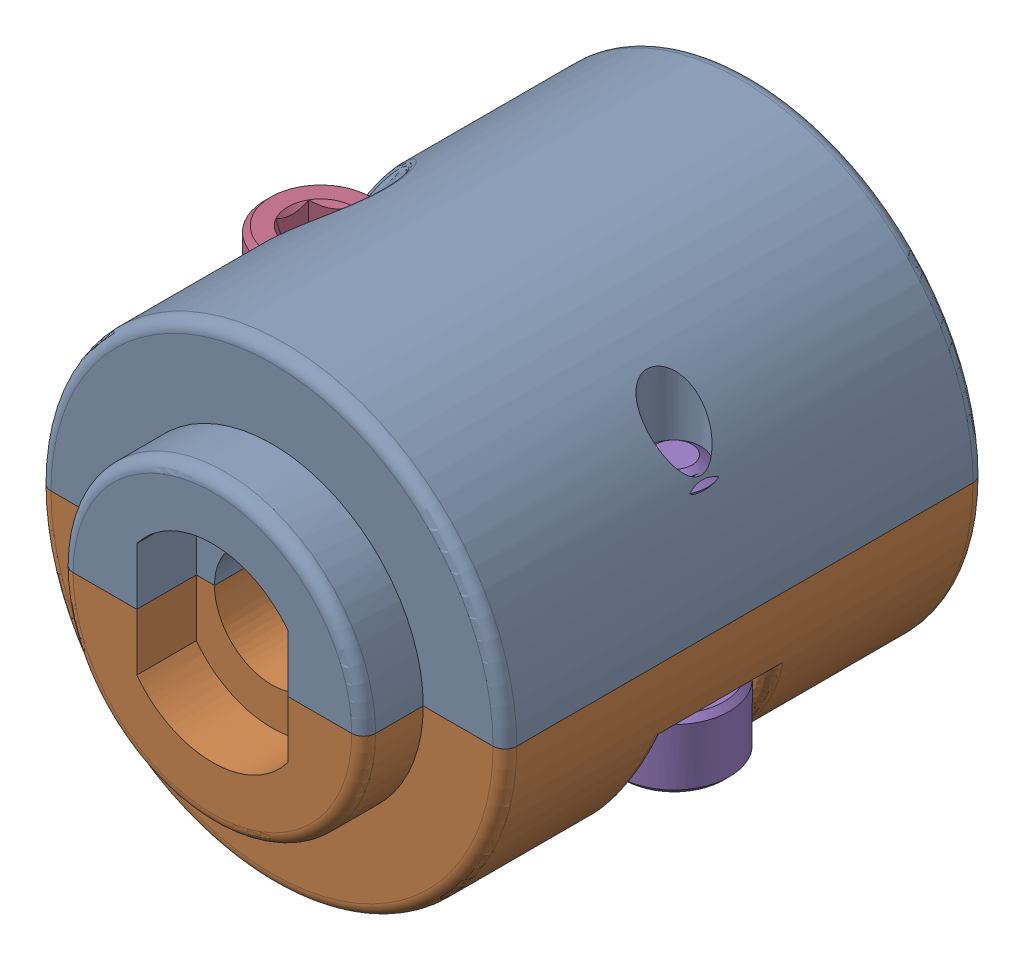
SolidWorks assembly 217-3195-200 Rev1, configuration Default. Lengths in mm.
Overall size (20.44 19.56 22.71).
5 component instances, 3 part files, 0 mates.
Components (placement in the parent):
- 217-3195-010 Rev1-1: 217-3195-010 Rev1 [Default] x (-1 0 0) z (0 0 1) size (19.61 11.78 22.71)
- 217-3195-010 Rev1-2: 217-3195-010 Rev1 [Default] at origin size (19.61 11.78 22.71)
- 217-2778-NCQ8A075-050M_1032_Nut_90545A111-1: 217-2778-NCQ8A075-050M_1032_Nut_90545A111 [Default] at (0 0 2.5527) x (-0.5 0.866025 0) z (0 0 1) size (9.53 11 3.39)
- 91251A107_91251A107-1: 91251A107_91251A107 [Default] at (-7.4168 -4.9375 -0.635) x (1 0 0) z (0 -1 0) size (4.65 4.65 10.79)
- 91251A107_91251A107-2: 91251A107_91251A107 [Default] at (7.4168 4.9375 -0.635) x (-0.837169 0 -0.546944) z (0 1 0) size (4.65 4.65 10.79)
